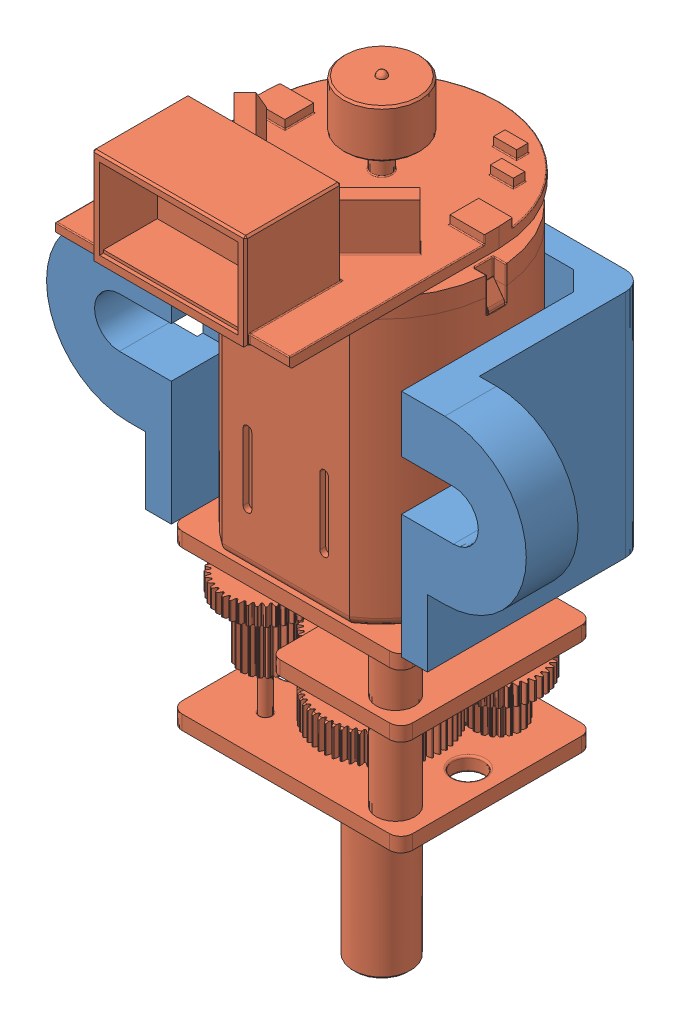
SolidWorks assembly N20+支架, configuration 默认. Lengths in mm.
Overall size (25 40 17.45).
2 component instances, 2 part files, 3 mates.
Components (placement in the parent):
- 电机固定n20-1: 电机固定n20 [默认] at (15.3425 -1.3248 19.34) size (25 12 11.32)
- JGA12-N20编码器DC马达[JGA12-N20-100K]-1: JGA12-N20编码器DC马达[JGA12-N20-100K] [JGA12-N20-100K] at (15.3425 7.6752 25.69) x (0 0 -1) z (0 1 0) size (17.2 12.2 40)
Mates (geometry in assembly coordinates):
- 重合1: coincident: plane of assembly; plane of assembly; plane of 电机固定n20-1 through (9.3425 -7.3248 20.69) normal (0 -1 0); plane of JGA12-N20编码器DC马达[JGA12-N20-100K]-1 through (9.9425 -7.3248 30.09) normal (0 1 0)
- 重合2: coincident: plane of assembly; plane of assembly; plane of 电机固定n20-1 through (15.3425 -1.3248 20.69) normal (0 0 1); plane of JGA12-N20编码器DC马达[JGA12-N20-100K]-1 through (18.6591 -7.3248 20.69) normal (0 0 -1)
- 相切1: tangent: plane of assembly; cylinder of assembly; plane of 电机固定n20-1 through (9.3425 -1.3248 19.34) normal (1 0 0); cylinder of JGA12-N20编码器DC马达[JGA12-N20-100K]-1 through (15.3425 -7.3248 25.69) axis (0 1 0) radius 6
